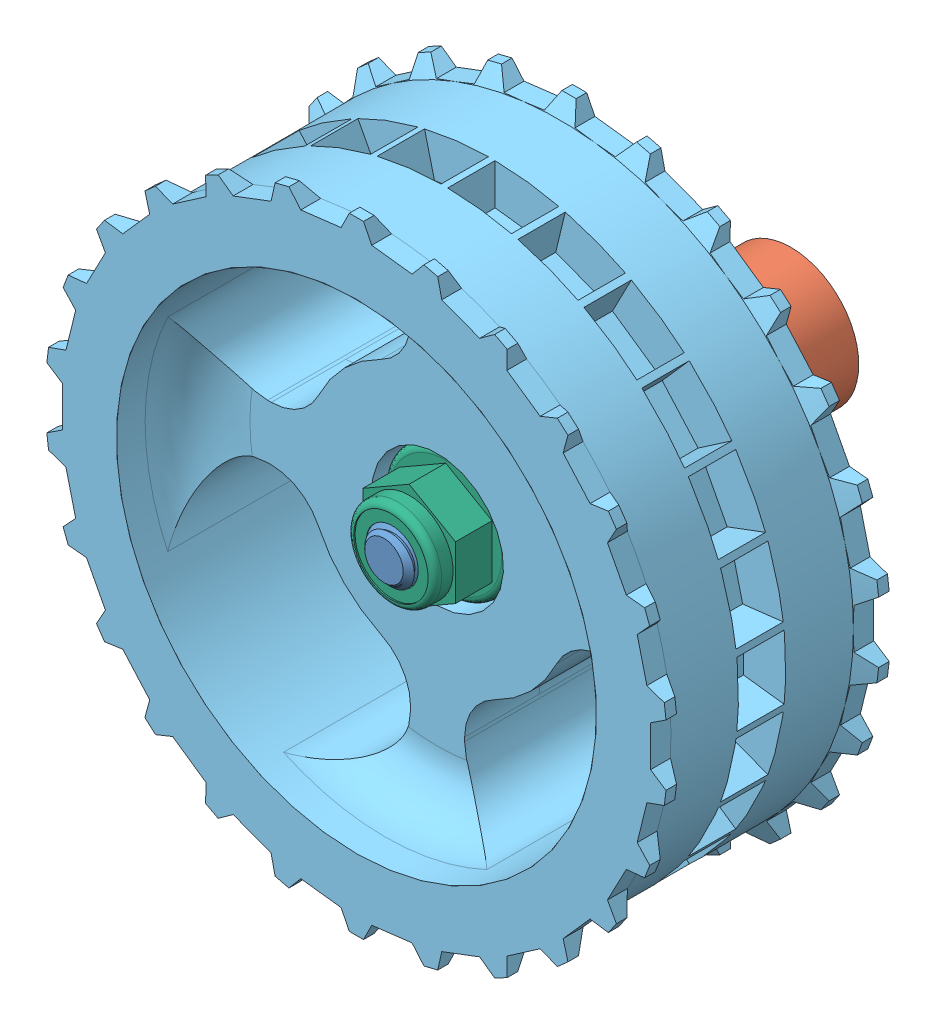
SolidWorks assembly wheel-free, configuration Default. Lengths in mm.
Overall size (45.78 46 33.24).
7 component instances, 6 part files, 14 mates.
Components (placement in the parent):
- wheel-free-shaft-1: wheel-free-shaft [Default] x (1 0 0) z (0 -1 0) size (6 31.32 6)
- wheel-free-bearing-1: wheel-free-bearing [Default] at (0 0 5.07) x (1 0 0) z (0 1 0) size (10 3.97 10)
- wheel-free-bearing-2: wheel-free-bearing [Default] at (0 0 15.74) x (0.774434 0.632655 0) z (-0.632655 0.774434 0) size (10 3.97 10)
- wheel-free-spacer-1: wheel-free-spacer [Default] at (0 0 16.74) x (0.90405 -0.427427 0) z (0.427427 0.90405 0) size (7 1 7)
- wheel-free-pin-1: wheel-free-pin [Default] at (0 -4.75 18.2) x (0.907276 0 -0.420536) z (0.420536 0 0.907276) size (2 9.5 2)
- wheel-body-1: wheel-body [Free] at (0 0 16.74) x (0 -1 0) z (0 0 1) size (46 45.78 16.5)
- M4-nut-1: M4-nut [Default] at (0 0 25.24) x (1 0 0) z (0 -1 0) size (9.3 5.45 9.3)
Mates (geometry in assembly coordinates):
- Coincident1: coincident anti-aligned: plane of wheel-free-shaft-1 through (0 0 0) normal (0 0 -1); plane of assembly through (0 0 0) normal (0 0 1)
- Concentric1: concentric anti-aligned: cylinder of wheel-free-shaft-1 through (0 0 20.6) axis (0 0 -1) radius 2.5; cylinder of wheel-free-bearing-1 through (0 0 1.1) axis (0 0 1) radius 2.5
- Coincident2: coincident anti-aligned: plane of wheel-free-shaft-1 through (0 0 1.1) normal (0 0 1); plane of wheel-free-bearing-1 through (0 0 1.1) normal (0 0 -1)
- Concentric2: concentric anti-aligned: cylinder of wheel-free-shaft-1 through (0 0 20.6) axis (0 0 -1) radius 2.5; cylinder of wheel-free-bearing-2 through (0 0 11.77) axis (0 0 1) radius 2.5
- Concentric3: concentric anti-aligned: cylinder of wheel-free-shaft-1 through (0 0 20.6) axis (0 0 -1) radius 2.5; cylinder of wheel-free-spacer-1 through (0 0 15.74) axis (0 0 1) radius 2.525
- Coincident3: coincident anti-aligned: plane of wheel-free-bearing-2 through (0 0 15.74) normal (0 0 1); plane of wheel-free-spacer-1 through (0 0 15.74) normal (0 0 -1)
- Concentric4: concentric aligned: cylinder of wheel-free-shaft-1 through (0 3.001 18.2) axis (0 -1 0) radius 1.05; cylinder of wheel-free-pin-1 through (0 4.75 18.2) axis (0 -1 0) radius 1
- Width1: width: plane of wheel-free-pin-1 through (0 4.75 18.2) normal (0 1 0); plane of wheel-free-pin-1 through (0 -4.75 18.2) normal (0 -1 0); cylinder of wheel-free-shaft-1 through (0 0 20.6) axis (0 0 -1) radius 2.5
- Concentric5: concentric aligned: cylinder of wheel-free-shaft-1 through (0 0 20.6) axis (0 0 -1) radius 2.5; cylinder of wheel-body-1 through (0 0 21.09) axis (0 0 -1) radius 2.7
- Parallel1: parallel anti-aligned: plane of wheel-free-pin-1 through (0 4.75 18.2) normal (0 1 0); plane of wheel-body-1 through (1.125 5.125 19.74) normal (0 -1 0)
- Distance1: distance = 0.54 mm anti-aligned: cylinder of wheel-free-pin-1 through (0 4.75 18.2) axis (0 -1 0) radius 1; plane of wheel-body-1 through (0 0 19.74) normal (0 0 -1)
- Coincident6: coincident anti-aligned: plane of wheel-free-spacer-1 through (0 0 16.74) normal (0 0 1); plane of wheel-body-1 through (0 0 16.74) normal (0 0 -1)
- Concentric6: concentric anti-aligned: cylinder of wheel-free-shaft-1 through (0 0 20.6) axis (0 0 -1) radius 2.5; cylinder of M4-nut-1 through (0 0 25.239) axis (0 0 1) radius 1.925
- Coincident7: coincident anti-aligned: plane of wheel-body-1 through (0 0 25.24) normal (0 0 1); plane of M4-nut-1 through (0 0 25.24) normal (0 0 -1)
